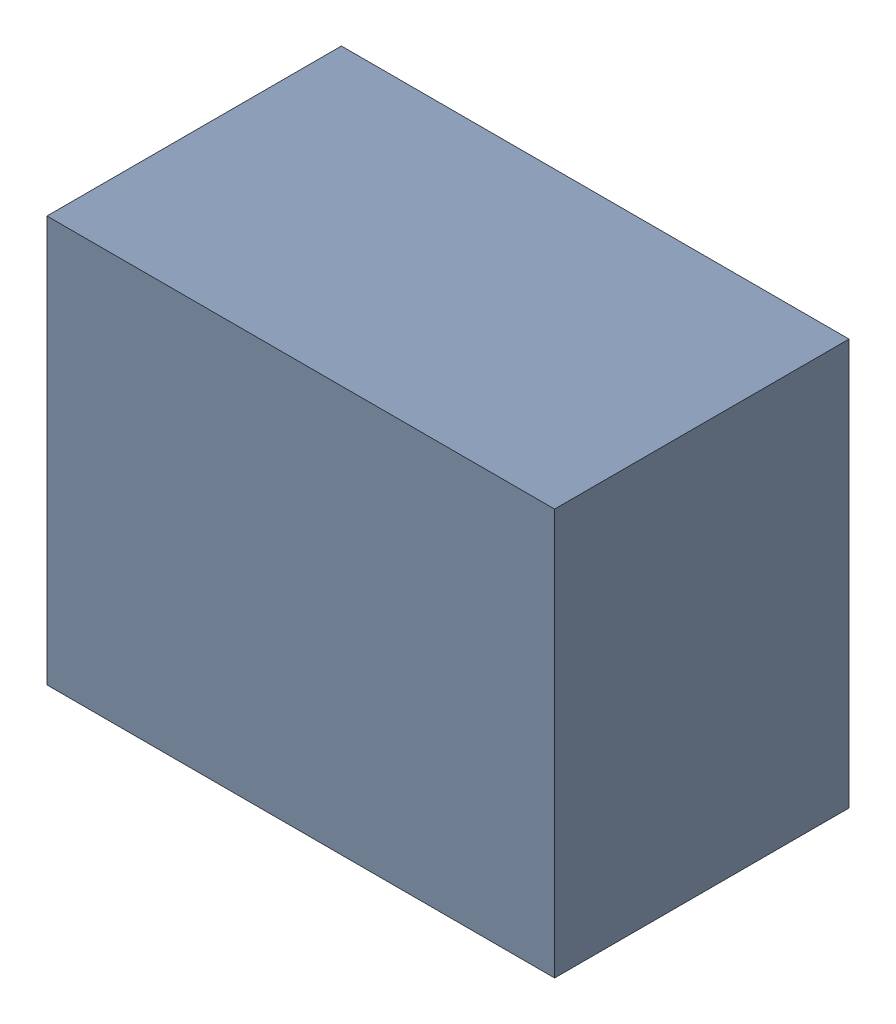
SolidWorks assembly U3, configuration Default. Lengths in mm.
Overall size (1 0.8 0.58).
2 component instances, 1 part files, 0 mates.
Components (placement in the parent):
- 810372112-1: 810372112 [Default] at (121.95 7.9 0.5) size (1 0.8 0.58)
  - Extruded_43-1: Extruded_43 [Default] at origin size (1 0.8 0.58)
